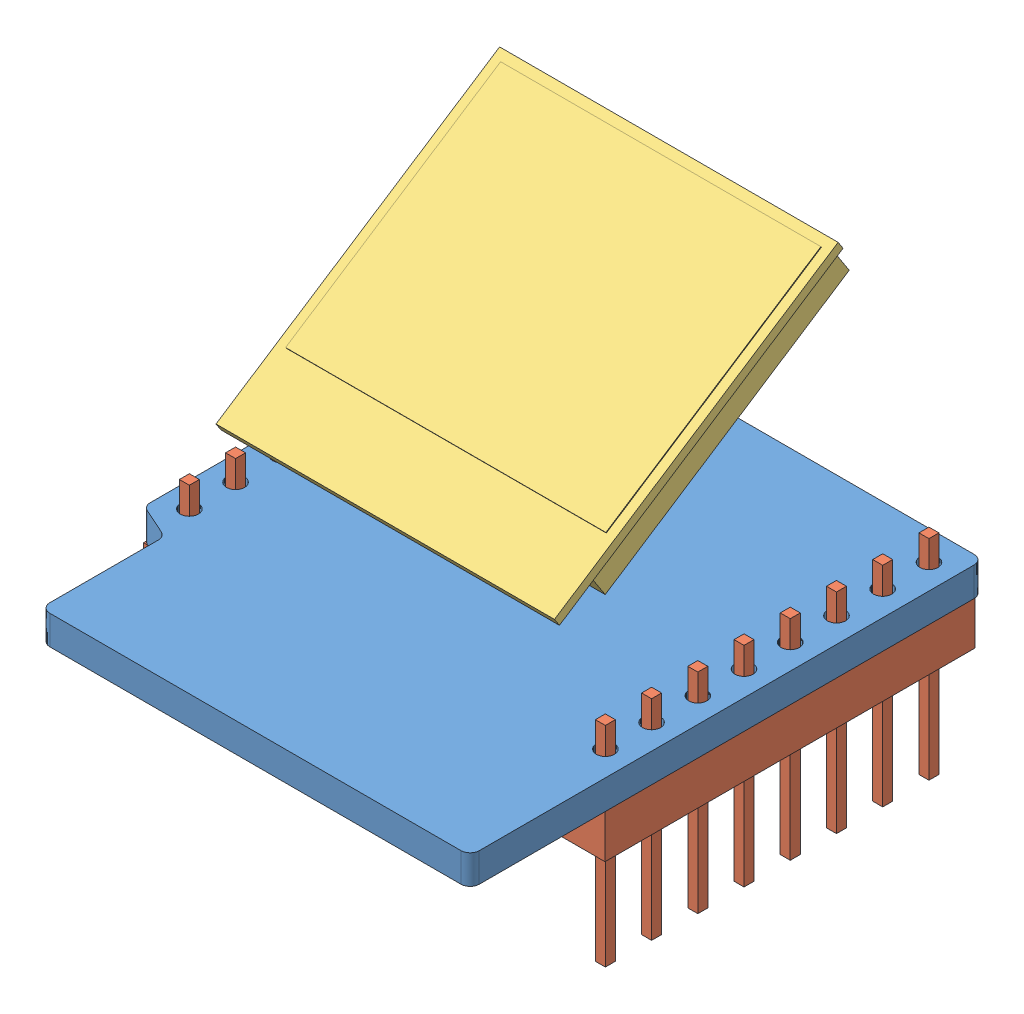
SolidWorks assembly LOLIN OLED shield 64x48, configuration Default. Lengths in mm.
Overall size (25.6 25.73 28.2).
4 component instances, 3 part files, 8 mates.
Components (placement in the parent):
- LOLIN template-1: LOLIN template [Default] at origin size (25.6 1.6 28.2)
- header_m8-1: header_m8 [Default] at (-11.43 -2.5 -27.85) x (0 0 1) z (-1 0 0) size (20.32 11.5 2.5)
- header_m8-2: header_m8 [Default] at (11.43 -2.5 -27.85) x (0 0 1) z (-1 0 0) size (20.32 11.5 2.5)
- oled_64x48-1: oled_64x48 [Default] at (0 6.6208 -8.4062) x (1 0 0) z (0 -0.545701 0.83798) size (18.6 3.55 18.6)
Mates (geometry in assembly coordinates):
- Coincident2: coincident anti-aligned: plane of breakout_template-1 through (0 0 0) normal (0 -1 0); plane of header_m8-1 through (-12.68 0 -27.85) normal (0 1 0)
- Coincident3: coincident anti-aligned: plane of breakout_template-1 through (0 0 0) normal (0 -1 0); plane of header_m8-2 through (10.18 0 -27.85) normal (0 1 0)
- Parallel1: parallel anti-aligned: plane of header_m8-1 through (-11.43 -2.5 -27.85) normal (-1 0 0)
- Parallel2: parallel anti-aligned: plane of header_m8-2 through (11.43 -2.5 -27.85) normal (-1 0 0)
- Coincident5: coincident aligned: line of breakout_template-1 through (-11.43 1.6 -26.58) axis (0 -1 0); line of header_m8-1 through (-11.43 -2.5 -26.58) axis (0 -1 0)
- Coincident6: coincident aligned: line of breakout_template-1 through (11.43 1.6 -26.58) axis (0 -1 0); line of header_m8-2 through (11.43 -2.5 -26.58) axis (0 -1 0)
- Coincident8: coincident aligned: plane of LOLIN template-1 through (0 0 0) normal (1 0 0); plane of oled_64x48-1 through (0 6.6208 -8.4062) normal (1 0 0)
- Concentric3: concentric aligned: circle of oled_64x48-1
